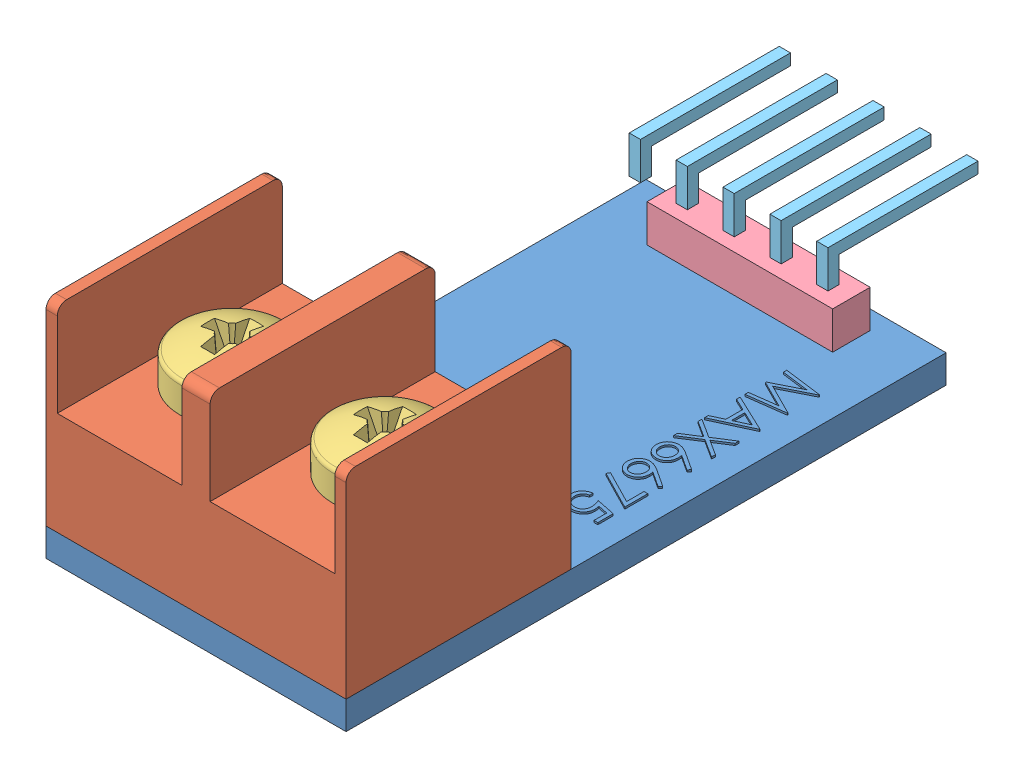
SolidWorks assembly MAX6675-K, configuration Default. Lengths in mm.
Overall size (16 12 37.7).
11 component instances, 5 part files, 10 mates.
Components (placement in the parent):
- MAX6675-K PCB-1: MAX6675-K PCB [Default] at origin size (16 1.6 32)
- MAX6675-K Connector-Block Base-1: MAX6675-K Connector-Block Base [Default] at (0 1.5 10) size (16 10.5 12)
- pan head cross recess screw_iso-2: pan head cross recess screw_iso [ISO 7045 - M3 x 4 - Z - 4N] at (-4.075 9.4 10) x (0 -1 0) z (0 0 1) size (6.35 5.6 5.6)
- pan head cross recess screw_iso-3: pan head cross recess screw_iso [ISO 7045 - M3 x 4 - Z - 4N] at (4.075 9.4 10) x (0 -1 0) z (0 0 1) size (6.35 5.6 5.6)
- MAX6675-K Header-1: MAX6675-K Header [Default] at (0 1.5 -14) x (0 0 -1) z (1 0 0) size (8.7 4 11.55)
  - Header-Base-1: Header-Base [Default] at origin size (2 2 9.9)
  - Header-Pin-1: Header-Pin [Default] at (0 2 3.7) x (0 0 -1) z (1 0 0) size (0.6 2 8)
  - Header-Pin-2: Header-Pin [Default] at (0 2 1.2) x (0 0 -1) z (1 0 0) size (0.6 2 8)
  - Header-Pin-3: Header-Pin [Default] at (0 2 -1.3) x (0 0 -1) z (1 0 0) size (0.6 2 8)
  - Header-Pin-4: Header-Pin [Default] at (0 2 -3.8) x (0 0 -1) z (1 0 0) size (0.6 2 8)
  - Header-Pin-5: Header-Pin [Default] at (0 2 -6.3) x (0 0 -1) z (1 0 0) size (0.6 2 8)
Mates (geometry in assembly coordinates):
- Coincident1: coincident: plane of MAX6675-K PCB-1 through (0 1.5 0) normal (0 1 0); plane of MAX6675-K Connector-Block Base-1 through (0 1.5 10) normal (0 -1 0)
- Coincident2: coincident: plane of MAX6675-K PCB-1 through (8 1.5 16) normal (1 0 0); plane of MAX6675-K Connector-Block Base-1 through (8 7 16) normal (1 0 0)
- Coincident3: coincident: plane of MAX6675-K PCB-1 through (8 1.5 16) normal (0 0 1); plane of MAX6675-K Connector-Block Base-1 through (-8 7 16) normal (0 0 1)
- Concentric2: concentric: cylinder of MAX6675-K Connector-Block Base-1 through (-4.075 7 10) axis (0 1 0) radius 1.25; cylinder of pan head cross recess screw_iso-2 through (-4.075 34.8 10) axis (0 1 0) radius 2.8
- Coincident5: coincident: plane of MAX6675-K Connector-Block Base-1 through (0 7 10) normal (0 1 0); plane of pan head cross recess screw_iso-2 through (-2.575 7 10) normal (0 -1 0)
- Concentric3: concentric: cylinder of MAX6675-K Connector-Block Base-1 through (4.075 7 10) axis (0 1 0) radius 1.25; cylinder of pan head cross recess screw_iso-3 through (4.075 34.8 10) axis (0 1 0) radius 2.8
- Coincident6: coincident: plane of MAX6675-K Connector-Block Base-1 through (0 7 10) normal (0 1 0); plane of pan head cross recess screw_iso-3 through (5.575 7 10) normal (0 -1 0)
- Coincident7: coincident: plane of MAX6675-K PCB-1 through (0 1.5 0) normal (0 1 0); plane of MAX6675-K Header-1/Header-Base-1 through (0 1.5 -14) normal (0 -1 0)
- Coincident8: coincident: plane of MAX6675-K Header-1/Header-Base-1 through (0 1.5 -14) normal (1 0 0); plane of assembly through (0 0 0) normal (1 0 0)
- Distance1: distance = 1 mm: plane of MAX6675-K Header-1/Header-Base-1 through (4.95 3.5 -15) normal (0 0 -1); plane of MAX6675-K PCB-1 through (8 1.5 -16) normal (0 0 -1)
